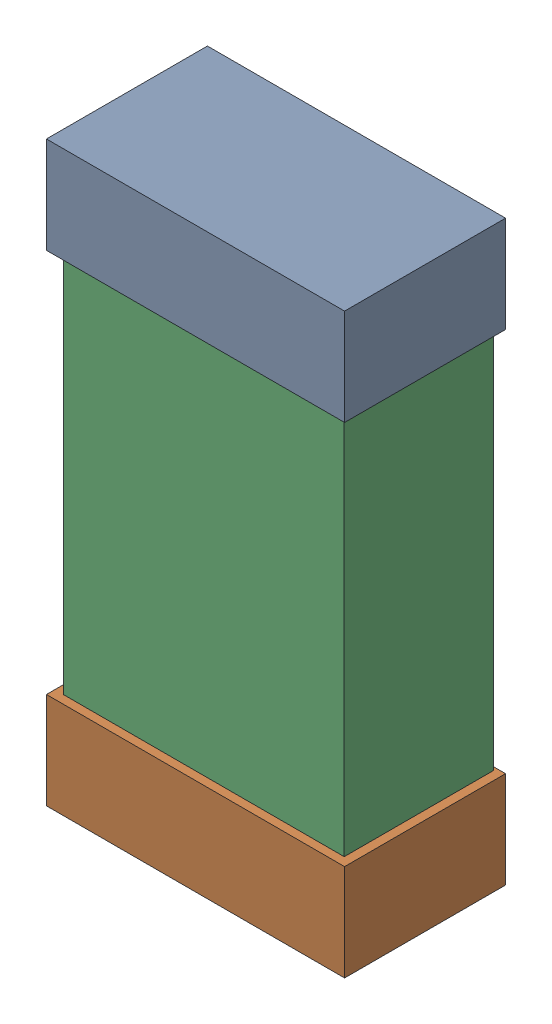
SolidWorks assembly R45, configuration Default. Lengths in mm.
Overall size (0.85 1.65 0.46).
6 component instances, 2 part files, 0 mates.
Components (placement in the parent):
- 432138512_14-1: 432138512_14 [Default] at (36.6501 52.3359 -0.8715) size (0.85 0.28 0.46)
  - Extruded-1: Extruded [Default] at origin size (0.85 0.28 0.46)
- 432138512_15-1: 432138512_15 [Default] at (36.6501 50.9643 -0.8715) size (0.85 0.28 0.46)
  - Extruded-1: Extruded [Default] at origin size (0.85 0.28 0.46)
- 432124816_7-1: 432124816_7 [Default] at (36.6501 51.6501 -0.8615) size (0.8 1.5 0.42)
  - Extruded (1)-1: Extruded (1) [Default] at origin size (0.8 1.5 0.42)
